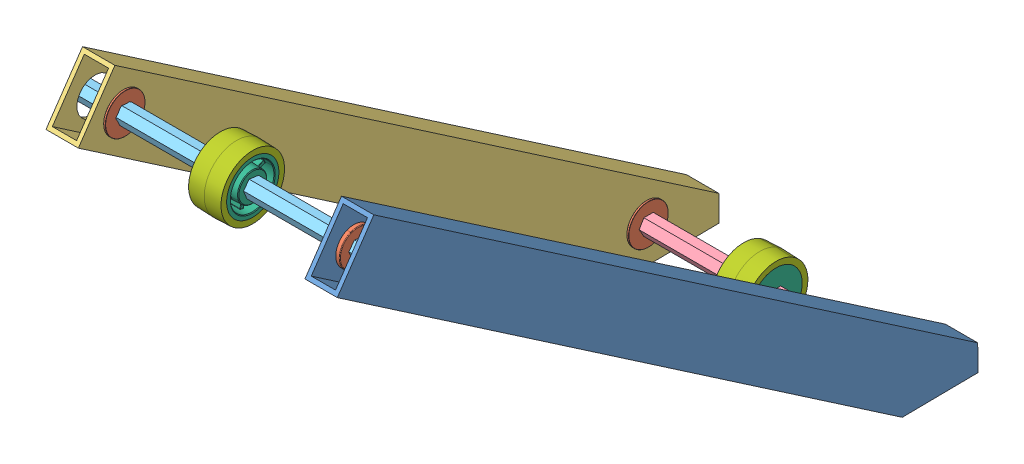
SolidWorks assembly Bottom Indexer, configuration Default. Lengths in mm.
Overall size (241.3 388.75 534.78).
14 component instances, 7 part files, 24 mates.
Components (placement in the parent):
- Bottom Box Bar-1: Bottom Box Bar [Default] at (679.4899 930.1324 1666.1793) x (0 -0.825583 0.564281) z (0 -0.564281 -0.825583) size (50.8 25.4 609.6)
- am-2986 FR8ZZ Hex Bearing.step-3: am-2986 FR8ZZ Hex Bearing.step [Default] at (660.4933 614.1774 1248.9284) x (0 0 1) z (-1 0 0) size (31.12 31.12 7.93)
- am-2986 FR8ZZ Hex Bearing.step-4: am-2986 FR8ZZ Hex Bearing.step [Default] at (660.4933 894.8298 1659.5422) x (0 -0.924225 -0.381849) z (-1 0 0) size (31.12 31.12 7.93)
- Bottom Box Bar B-1: Bottom Box Bar B [Default] at (476.2899 930.1324 1666.1793) x (0 -0.825583 0.564281) z (0 -0.564281 -0.825583) size (50.8 25.4 609.6)
- am-2986 FR8ZZ Hex Bearing.step-9: am-2986 FR8ZZ Hex Bearing.step [Default] at (469.8866 894.8298 1659.5422) x (0 0 -1) z (1 0 0) size (31.12 31.12 7.93)
- am-2986 FR8ZZ Hex Bearing.step-10: am-2986 FR8ZZ Hex Bearing.step [Default] at (469.8866 614.1774 1248.9284) x (0 0 -1) z (1 0 0) size (31.12 31.12 7.93)
- bottom second rod-1: bottom second rod [Default] at (463.5899 614.1774 1248.9284) x (1 0 0) z (0 -0.866025 -0.5) size (203.2 12.7 14.66)
- bottom first rod-2: bottom first rod [Default] at (438.1899 894.8298 1659.5422) x (1 0 0) z (0 -0.792804 0.609477) size (228.6 12.7 14.66)
- am-3155 2IN 500Hex Stealth Wheel REV2.STEP-1: am-3155 2IN 500Hex Stealth Wheel REV2.STEP [Default] at (552.4899 606.4819 1277.5388) x (0 0.866025 -0.5) z (-1 0 0) size (57.25 57.25 25.4)
  - 2in Wheel Intergrated 0500 HEX Hub.STEP-1: 2in Wheel Intergrated 0500 HEX Hub.STEP [Default] at (20.955 20.955 -12.7) x (-0.866025 0.5 0) z (0 0 -1) size (41.91 41.91 25.4)
  - 2in Tread.STEP-1: 2in Tread.STEP [Default] at (20.955 20.955 -12.7) x (0 0 -1) z (1 0 0) size (25.4 50.8 50.8)
- am-3155 2IN 500Hex Stealth Wheel REV2.STEP-2: am-3155 2IN 500Hex Stealth Wheel REV2.STEP [Default] at (577.8899 924.2456 1663.4241) x (0 -0.792804 0.609477) z (1 0 0) size (57.25 57.25 25.4)
  - 2in Wheel Intergrated 0500 HEX Hub.STEP-1: 2in Wheel Intergrated 0500 HEX Hub.STEP [Default] at (20.955 20.955 -12.7) x (-0.866025 0.5 0) z (0 0 -1) size (41.91 41.91 25.4)
  - 2in Tread.STEP-1: 2in Tread.STEP [Default] at (20.955 20.955 -12.7) x (0 0 -1) z (1 0 0) size (25.4 50.8 50.8)
Mates (geometry in assembly coordinates):
- Coincident32: coincident anti-aligned: plane of Bottom Box Bar-1 through (654.0899 586.1464 1162.9042) normal (-1 0 0); plane of am-2986 FR8ZZ Hex Bearing.step-4 through (654.0899 881.9184 1654.2078) normal (1 0 0)
- Coincident33: coincident anti-aligned: plane of Bottom Box Bar-1 through (654.0899 586.1464 1162.9042) normal (-1 0 0); plane of am-2986 FR8ZZ Hex Bearing.step-3 through (654.0899 614.1774 1262.8984) normal (1 0 0)
- Concentric6: concentric anti-aligned: cylinder of Bottom Box Bar-1 through (657.2649 894.8298 1659.5422) axis (-1 0 0) radius 14.2875; cylinder of am-2986 FR8ZZ Hex Bearing.step-4 through (652.5659 894.8298 1659.5422) axis (1 0 0) radius 14.2875
- Coincident35: coincident anti-aligned: plane of Bottom Box Bar B-1 through (476.2899 586.1464 1162.9042) normal (1 0 0); circle of am-2986 FR8ZZ Hex Bearing.step-10
- Coincident36: coincident anti-aligned: plane of Bottom Box Bar B-1 through (476.2899 586.1464 1162.9042) normal (1 0 0); circle of am-2986 FR8ZZ Hex Bearing.step-9
- Concentric8: concentric aligned: cylinder of Bottom Box Bar B-1 through (476.2899 894.8298 1659.5422) axis (-1 0 0) radius 14.2875; cylinder of am-2986 FR8ZZ Hex Bearing.step-9 through (477.8139 894.8298 1659.5422) axis (-1 0 0) radius 14.2875
- Distance3: distance = 228.6 mm anti-aligned: plane of Bottom Box Bar-1 through (679.4899 586.1464 1162.9042) normal (1 0 0); plane of Bottom Box Bar B-1 through (450.8899 586.1464 1162.9042) normal (-1 0 0)
- Coincident38: coincident aligned: plane of Bottom Box Bar-1 through (679.4899 930.1324 1666.1793) normal (0 0.564281 0.825583); plane of Bottom Box Bar B-1 through (476.2899 930.1324 1666.1793) normal (0 0.564281 0.825583)
- Coincident39: coincident aligned: plane of Bottom Box Bar-1 through (679.4899 586.1464 1162.9042) normal (0 0.825583 -0.564281); plane of Bottom Box Bar B-1 through (476.2899 586.1464 1162.9042) normal (0 0.825583 -0.564281)
- Width1: width aligned: plane of bottom second rod-1 through (666.7899 614.1774 1248.9284) normal (1 0 0); plane of Bottom Box Bar B-1 through (463.5899 614.1774 1248.9284) normal (-1 0 0); plane of bottom second rod-1 through (454.0649 583.5252 1164.6958) normal (1 0 0); plane of Bottom Box Bar-1 through (676.3149 583.5252 1164.6958) normal (-1 0 0)
- Coincident40: coincident anti-aligned: plane of am-2986 FR8ZZ Hex Bearing.step-3 through (652.5659 607.8274 1252.5946) normal (0 1 0); plane of bottom second rod-1 through (666.7899 607.8274 1252.5946) normal (0 -1 0)
- Coincident41: coincident anti-aligned: plane of am-2986 FR8ZZ Hex Bearing.step-3 through (652.5659 620.5274 1252.5946) normal (0 -0.5 -0.866025); plane of bottom second rod-1 through (666.7899 620.5274 1252.5946) normal (0 0.5 0.866025)
- Coincident45: coincident aligned: plane of bottom second rod-1 through (666.7899 614.1774 1248.9284) normal (1 0 0); plane of bottom first rod-2 through (666.7899 894.8298 1659.5422) normal (1 0 0)
- Coincident46: coincident anti-aligned: plane of am-2986 FR8ZZ Hex Bearing.step-4 through (652.5659 893.8662 1652.2735) normal (0 -0.381849 0.924225); plane of bottom first rod-2 through (666.7899 893.8662 1652.2735) normal (0 0.381849 -0.924225)
- Coincident48: coincident anti-aligned: plane of am-2986 FR8ZZ Hex Bearing.step-4 through (652.5659 900.6429 1655.0733) normal (0 -0.991327 0.131421); plane of bottom first rod-2 through (666.7899 900.6429 1655.0733) normal (0 0.991327 -0.131421)
- Coincident49: coincident anti-aligned: plane of bottom second rod-1 through (666.7899 620.5274 1245.2622) normal (0 1 0); plane of am-3155 2IN 500Hex Stealth Wheel REV2.STEP-1/2in Wheel Intergrated 0500 HEX Hub.STEP-1 through (577.8899 620.5274 1252.5946) normal (0 -1 0)
- Coincident51: coincident anti-aligned: plane of bottom second rod-1 through (666.7899 620.5274 1252.5946) normal (0 0.5 0.866025); plane of am-3155 2IN 500Hex Stealth Wheel REV2.STEP-1/2in Wheel Intergrated 0500 HEX Hub.STEP-1 through (577.8899 614.152 1256.2754) normal (0 -0.5 -0.866025)
- Width2: width anti-aligned: plane of am-3155 2IN 500Hex Stealth Wheel REV2.STEP-1/2in Tread.STEP-1 through (577.8899 601.6737 1227.3008) normal (1 0 0); plane of am-2986 FR8ZZ Hex Bearing.step-3 through (552.4899 601.6737 1227.3008) normal (-1 0 0); plane of am-3155 2IN 500Hex Stealth Wheel REV2.STEP-1/2in Tread.STEP-1 through (652.5659 614.1774 1264.4859) normal (-1 0 0); plane of am-2986 FR8ZZ Hex Bearing.step-10 through (477.8139 614.1774 1233.3709) normal (1 0 0)
- Coincident62: coincident anti-aligned: plane of bottom first rod-2 through (666.7899 893.8662 1652.2735) normal (0 0.381849 -0.924225); plane of am-3155 2IN 500Hex Stealth Wheel REV2.STEP-2/2in Wheel Intergrated 0500 HEX Hub.STEP-1 through (552.4899 893.8933 1652.2847) normal (0 -0.381849 0.924225)
- Coincident64: coincident anti-aligned: plane of bottom first rod-2 through (666.7899 889.0167 1664.0111) normal (0 -0.991327 0.131421); plane of am-3155 2IN 500Hex Stealth Wheel REV2.STEP-2/2in Wheel Intergrated 0500 HEX Hub.STEP-1 through (552.4899 889.0244 1664.0693) normal (0 0.991327 -0.131421)
- Width3: width anti-aligned: plane of am-3155 2IN 500Hex Stealth Wheel REV2.STEP-2/2in Tread.STEP-1 through (552.4899 879.6504 1639.7969) normal (-1 0 0); plane of am-2986 FR8ZZ Hex Bearing.step-9 through (577.8899 879.6504 1639.7969) normal (1 0 0); plane of am-3155 2IN 500Hex Stealth Wheel REV2.STEP-2/2in Tread.STEP-1 through (477.8139 894.8298 1643.9847) normal (1 0 0); plane of am-2986 FR8ZZ Hex Bearing.step-4 through (652.5659 880.4512 1653.6016) normal (-1 0 0)
- Concentric10: concentric anti-aligned: cylinder of Bottom Box Bar-1 through (657.2649 614.1774 1248.9284) axis (-1 0 0) radius 14.2875; cylinder of am-2986 FR8ZZ Hex Bearing.step-3 through (652.5659 614.1774 1248.9284) axis (1 0 0) radius 14.2875
- Concentric11: concentric anti-aligned: cylinder of Bottom Box Bar B-1 through (473.1149 614.1774 1248.9284) axis (1 0 0) radius 14.2875; cylinder of am-2986 FR8ZZ Hex Bearing.step-10 through (477.8139 614.1774 1248.9284) axis (-1 0 0) radius 14.2875
- Coincident66: coincident anti-aligned: plane of am-2986 FR8ZZ Hex Bearing.step-10 through (477.8139 607.8274 1252.5946) normal (0 0.5 -0.866025); plane of bottom second rod-1 through (666.7899 614.1774 1256.2607) normal (0 -0.5 0.866025)
